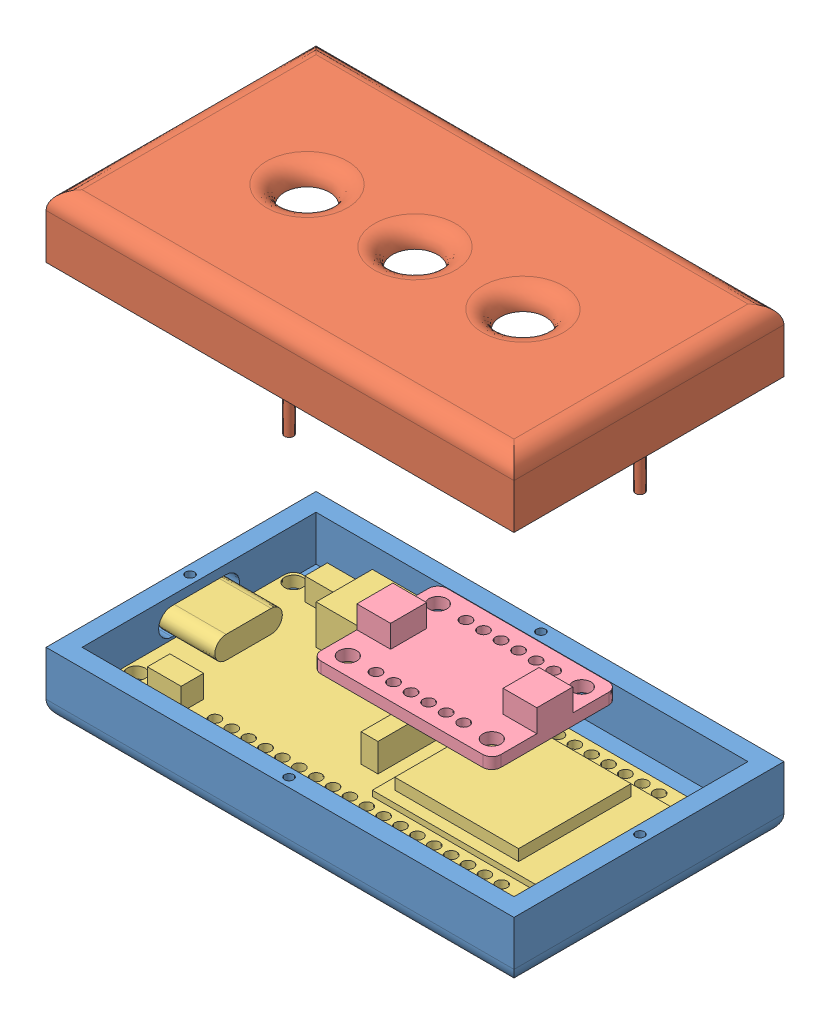
SolidWorks assembly BoxAssembly, configuration Default. Lengths in mm.
Overall size (66.04 64.83 38.1).
4 component instances, 4 part files, 3 mates.
Components (placement in the parent):
- Box-Bottom-1: Box-Bottom [Default] at (-27.7446 21.4683 85.7743) size (66.04 8.89 38.1)
- Box-Top-1: Box-Top [Default] at (-27.7446 86.2936 47.6743) x (1 0 0) z (0 0 -1) size (66.04 13.97 38.1)
- micro-1: micro [Default] at (-26.1486 24.0083 79.4221) size (60.32 7.14 25.4)
- Accelerometer-1: Accelerometer [Default] at (-6.4993 30.2206 69.5066) size (25.4 4.76 17.78)
Mates (geometry in assembly coordinates):
- Concentric1: concentric aligned: cylinder of Box-Bottom-1 through (5.2754 25.2783 48.9443) axis (0 1 0) radius 0.635; cylinder of Box-Top-1 through (5.2754 72.3236 48.9443) axis (0 1 0) radius 0.635
- Concentric2: concentric aligned: cylinder of Box-Bottom-1 through (-26.4746 25.2783 66.7243) axis (0 1 0) radius 0.635; cylinder of Box-Top-1 through (-26.4746 72.3236 66.7243) axis (0 1 0) radius 0.635
- Coincident2: coincident anti-aligned: plane of Box-Bottom-1 through (-27.7446 24.0083 85.7743) normal (0 1 0); plane of micro-1 through (-26.1486 24.0083 79.4221) normal (0 -1 0)
